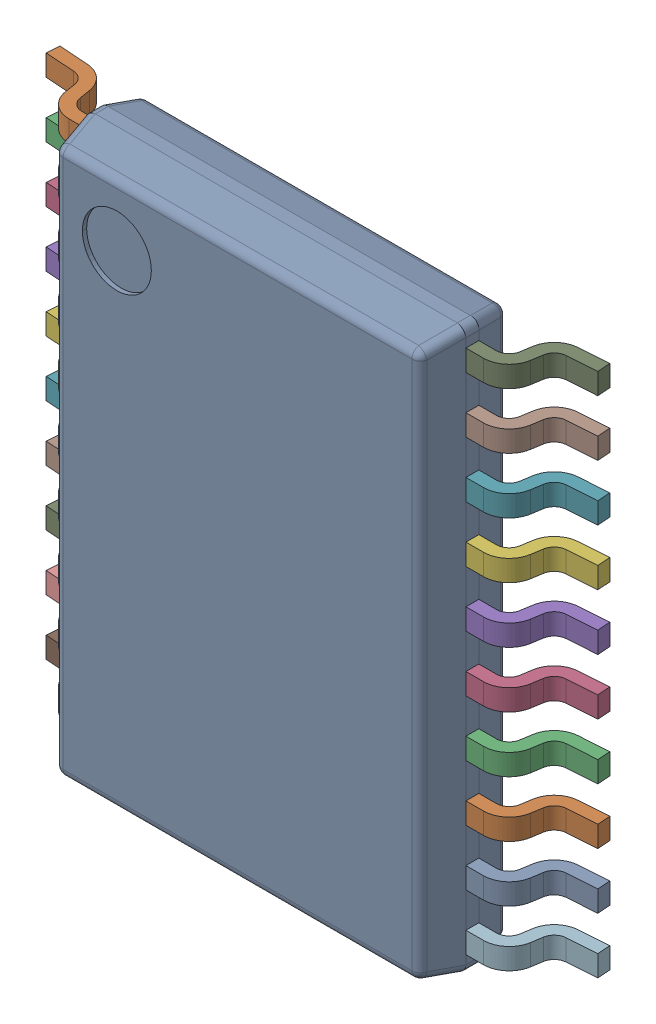
SolidWorks assembly 9651432272_1.step, configuration Default. Lengths in mm.
Overall size (6.4 6.5 1.13).
21 component instances, 2 part files, 0 mates.
Components (placement in the parent):
- BODY-TSSOP_1.step-11: BODY-TSSOP_1.step [Default] at (0 0 0.68) x (1 0 0) z (0 -1 0) size (4.4 1 6.5)
- LEAD-TSSOP_1.step-242: LEAD-TSSOP_1.step [Default] at (-2.575 2.925 0.25) x (0 -1 0) z (-1 0 0) size (0.24 0.68 1)
- LEAD-TSSOP_1.step-243: LEAD-TSSOP_1.step [Default] at (-2.575 2.275 0.25) x (0 -1 0) z (-1 0 0) size (0.24 0.68 1)
- LEAD-TSSOP_1.step-244: LEAD-TSSOP_1.step [Default] at (-2.575 1.625 0.25) x (0 -1 0) z (-1 0 0) size (0.24 0.68 1)
- LEAD-TSSOP_1.step-245: LEAD-TSSOP_1.step [Default] at (-2.575 0.975 0.25) x (0 -1 0) z (-1 0 0) size (0.24 0.68 1)
- LEAD-TSSOP_1.step-246: LEAD-TSSOP_1.step [Default] at (-2.575 0.325 0.25) x (0 -1 0) z (-1 0 0) size (0.24 0.68 1)
- LEAD-TSSOP_1.step-247: LEAD-TSSOP_1.step [Default] at (-2.575 -0.325 0.25) x (0 -1 0) z (-1 0 0) size (0.24 0.68 1)
- LEAD-TSSOP_1.step-248: LEAD-TSSOP_1.step [Default] at (-2.575 -0.975 0.25) x (0 -1 0) z (-1 0 0) size (0.24 0.68 1)
- LEAD-TSSOP_1.step-249: LEAD-TSSOP_1.step [Default] at (-2.575 -1.625 0.25) x (0 -1 0) z (-1 0 0) size (0.24 0.68 1)
- LEAD-TSSOP_1.step-250: LEAD-TSSOP_1.step [Default] at (-2.575 -2.275 0.25) x (0 -1 0) z (-1 0 0) size (0.24 0.68 1)
- LEAD-TSSOP_1.step-251: LEAD-TSSOP_1.step [Default] at (-2.575 -2.925 0.25) x (0 -1 0) z (-1 0 0) size (0.24 0.68 1)
- LEAD-TSSOP_1.step-252: LEAD-TSSOP_1.step [Default] at (2.575 -2.925 0.25) x (0 1 0) z (1 0 0) size (0.24 0.68 1)
- LEAD-TSSOP_1.step-253: LEAD-TSSOP_1.step [Default] at (2.575 -2.275 0.25) x (0 1 0) z (1 0 0) size (0.24 0.68 1)
- LEAD-TSSOP_1.step-254: LEAD-TSSOP_1.step [Default] at (2.575 -1.625 0.25) x (0 1 0) z (1 0 0) size (0.24 0.68 1)
- LEAD-TSSOP_1.step-255: LEAD-TSSOP_1.step [Default] at (2.575 -0.975 0.25) x (0 1 0) z (1 0 0) size (0.24 0.68 1)
- LEAD-TSSOP_1.step-256: LEAD-TSSOP_1.step [Default] at (2.575 -0.325 0.25) x (0 1 0) z (1 0 0) size (0.24 0.68 1)
- LEAD-TSSOP_1.step-257: LEAD-TSSOP_1.step [Default] at (2.575 0.325 0.25) x (0 1 0) z (1 0 0) size (0.24 0.68 1)
- LEAD-TSSOP_1.step-258: LEAD-TSSOP_1.step [Default] at (2.575 0.975 0.25) x (0 1 0) z (1 0 0) size (0.24 0.68 1)
- LEAD-TSSOP_1.step-259: LEAD-TSSOP_1.step [Default] at (2.575 1.625 0.25) x (0 1 0) z (1 0 0) size (0.24 0.68 1)
- LEAD-TSSOP_1.step-260: LEAD-TSSOP_1.step [Default] at (2.575 2.275 0.25) x (0 1 0) z (1 0 0) size (0.24 0.68 1)
- LEAD-TSSOP_1.step-261: LEAD-TSSOP_1.step [Default] at (2.575 2.925 0.25) x (0 1 0) z (1 0 0) size (0.24 0.68 1)
